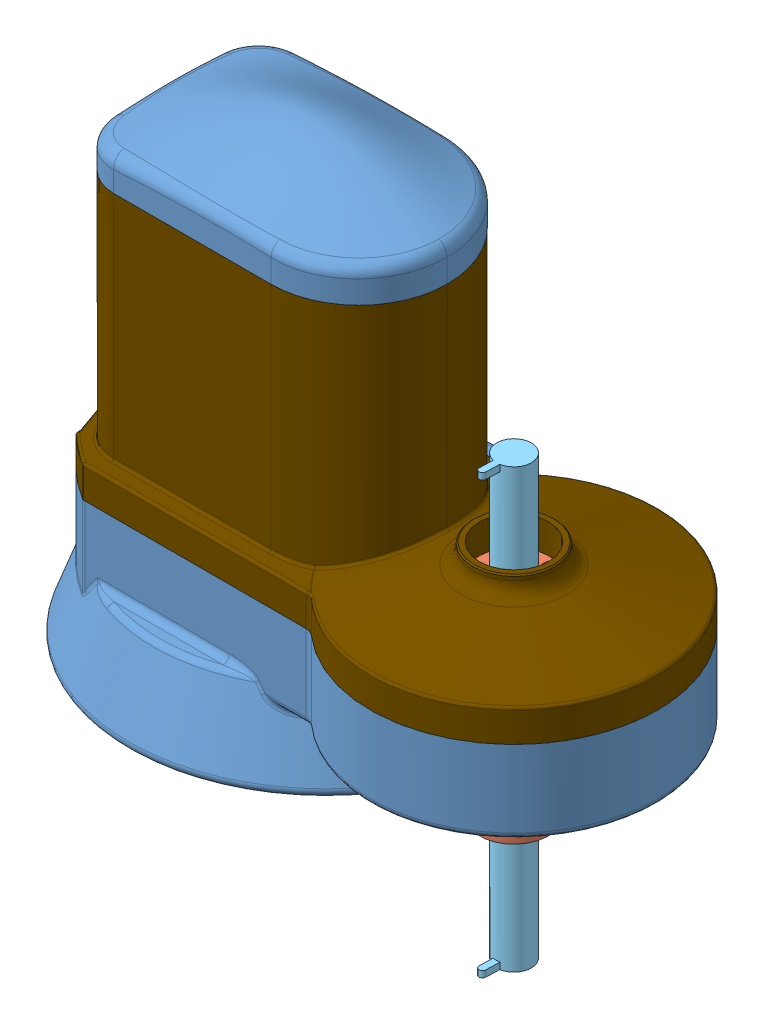
SolidWorks assembly 3rdgear-drive, configuration Default. Lengths in mm.
Overall size (465.65 484.88 318.82).
28 component instances, 23 part files, 43 mates.
Components (placement in the parent):
- block-1: block [Default] at (113.1408 70.2155 28.8884) size (448.1 118.47 307.8)
- lock3-1: lock3 [Default] at (1.0097 141.2577 38.6575) x (-0.07621 0 0.997092) z (0 -1 0) size (153.17 153.13 253.48) (flexible)
  - Part1 - Copy-1: Part1 - Copy [Default] at (-9.0719 9.4939 -127.4378) size (88.21 88.13 251.48)
  - 3rd Gear-1: 3rd Gear [Default] at (-9.0719 9.4939 -34.8178) x (0.981754 -0.190153 0) z (0.190153 0.981754 0) size (89.95 22.5 89.85)
  - 4th-1: 4th [Default] at (-9.0719 9.4939 -94.2778) x (0.930629 -0.365964 0) z (0.365964 0.930629 0) size (89.95 21.35 89.85)
  - 4th Mesh - Copy-1: 4th Mesh - Copy [Default] at (-9.0719 9.4939 -71.9278) x (0.992326 0.123646 0) z (-0.123646 0.992326 0) size (86.29 9.5 85.96)
  - gear3 mesh-1: gear3 mesh [Default] at (-9.0719 9.4939 -45.7778) x (0.370817 0.928706 0) z (-0.928706 0.370817 0) size (86.48 9.6 86.41)
  - Part3-1: Part3 [Default] at (-9.0719 9.4939 -49.6467) x (0.888761 -0.458371 0) z (-0.458371 -0.888761 0) size (106.2 22 106.2)
  - reverse-1: reverse [Default] at (-9.0719 9.4939 19.6169) x (0.555504 -0.831514 0) z (0.831514 0.555504 0) size (107.95 22 107.84)
  - 2nd gear-1: 2nd gear [Default] at (-9.0719 9.4939 -1.7178) x (0.052404 0.998626 0) z (-0.998626 0.052404 0) size (102.15 21.6 102.2)
  - reverse mesh-1: reverse mesh [Default] at (-9.0719 9.4939 4.6222) x (0.455242 -0.890368 0) z (0.890368 0.455242 0) size (80 8.5 80)
  - reverse mesh-2: reverse mesh [Default] at (-9.0719 9.4939 32.2222) x (-0.823291 -0.56762 0) z (-0.56762 0.823291 0) size (80 8.5 80)
  - 1st gear-1: 1st gear [Default] at (-9.0719 9.4939 41.2222) x (0.904554 0.426359 0) z (0.426359 -0.904554 0) size (115.11 23.6 115.04)
  - base-1: base [Default] at (-9.0719 9.4939 61.5422) x (-0.997092 0.07621 0) z (0.07621 0.997092 0) size (110 64.6 106)
- 1stshaft-1: 1stshaft [Default] at (-69.065 -17.9645 -6.5031) x (0.285789 0 -0.958293) z (0 1 0) size (77.36 77.56 310)
- bearing1-1: bearing1 [Default] at (-69.065 62.5355 -6.5031) x (0.746597 0 -0.665277) z (-0.665277 0 -0.746597) size (44.38 14.99 44.48)
- bearing2-1: bearing2 [Default] at (-69.065 250.9655 -6.5031) x (0.941122 0 -0.338068) z (0.338068 0 0.941122) size (59.38 14.43 59.22)
- rev-1: rev [Default] at (-83.7633 57.8155 52.0494) x (1 0 0) z (0 0 1) size (29.99 110 29.95)
- rev2-1: rev2 [Default] at (-83.7633 102.8155 52.0494) x (-0.962662 0 -0.270707) z (0.270707 0 -0.962662) size (59.97 20 59.87)
- blockup-1: blockup [Default] at (113.1408 95.0155 28.8884) size (399.91 205.51 224)
- blockup - Copy-1: blockup - Copy [Default] at (113.1408 95.0155 28.8884) size (222.45 55.95 144.6)
- diff-1: diff [Default] at (113.1408 30.6155 28.8884) x (-0.420076 0 -0.907489) z (0.907489 0 -0.420076) size (195.12 146.24 195.18)
- diffgearsmall-1: diffgearsmall [Default] at (115.5517 17.1155 34.0965) x (-0.420076 0 -0.907489) z (-0.528841 0.81265 0.2448) size (22.67 53.82 54.31)
- diffgearsmall-2: diffgearsmall [Default] at (110.73 17.1155 23.6804) x (0.420076 0 0.907489) z (0.876152 0.260519 -0.40557) size (22.67 53.82 54.31)
- diffgearbig-1: diffgearbig [Default] at (113.1408 17.0565 28.8884) x (0 1 0) z (-0.998475 0 -0.055198) size (22.67 61.01 61.56)
- diffgearbig-2: diffgearbig [Default] at (113.1408 17.7745 28.8884) x (0 -1 0) z (-0.870436 0 -0.492282) size (22.67 61.01 61.56)
- axle-1: axle [Default] at (113.1408 38.0355 28.8884) x (-0.999515 0 -0.031126) z (0 1 0) size (27 40.03 150)
- axle-2: axle [Default] at (113.1408 -3.2045 28.8884) x (0.999506 0 0.031435) z (0 -1 0) size (27 40.03 150)
Mates (geometry in assembly coordinates):
- Concentric1: concentric anti-aligned: cylinder of block-1 through (-7.7652 184.5592 28.8884) axis (0 -1 0) radius 32.5; cylinder of lock3-1/Part1 - Copy-1 through (-7.7652 17.2155 28.8884) axis (0 1 0) radius 17.5
- Concentric2: concentric aligned: cylinder of block-1 through (9.7348 15.2155 -16.1116) axis (0 1 0) radius 4; cylinder of lock3-1/base-1 through (9.7348 55.2155 -16.1116) axis (0 1 0) radius 4
- Coincident2: coincident anti-aligned: plane of block-1 through (-170.2735 70.2155 89.7919) normal (0 1 0); plane of lock3-1/base-1 through (17.939 70.2155 -28.6691) normal (0 -1 0)
- Concentric3: concentric anti-aligned: circle of block-1; cylinder of 1stshaft-1 through (-69.065 277.5355 -6.5031) axis (0 -1 0) radius 17.5
- Coincident3: coincident aligned: plane of lock3-1/4th-1 through (-7.7652 235.5355 28.8884) normal (0 1 0); plane of 1stshaft-1 through (-69.065 235.5355 -6.5031) normal (0 1 0)
- Concentric4: concentric aligned: cylinder of 1stshaft-1 through (-69.065 214.5355 -6.5031) axis (0 -1 0) radius 16.75; cone of bearing1-1 through (-69.065 65.7601 -6.5031) axis (0 -1 0)
- Tangent1: tangent: plane of 1stshaft-1 through (-69.065 77.5355 -6.5031) normal (0 1 0); torus of bearing1-1
- Concentric5: concentric anti-aligned: cone of 1stshaft-1 through (-69.065 251.5355 -6.5031) axis (0 1 0); cylinder of bearing2-1 through (-69.065 233.5355 -6.5031) axis (0 -1 0) radius 22.5514
- Distance1: distance = 1 mm anti-aligned: plane of bearing2-1 through (-45.7332 236.5355 -14.8843) normal (0 -1 0); plane of 1stshaft-1 through (-69.065 235.5355 -6.5031) normal (0 1 0)
- Coincident5: coincident anti-aligned: plane of block-1 through (37.6425 57.8155 -51.1116) normal (0 1 0); plane of rev-1 through (-83.7633 57.8155 52.0494) normal (0 -1 0)
- Concentric6: concentric aligned: cylinder of block-1 through (-83.7633 112.6419 52.0494) axis (0 -1 0) radius 10; cylinder of rev-1 through (-83.7633 167.8155 52.0494) axis (0 -1 0) radius 10
- Concentric7: concentric aligned: cylinder of rev-1 through (-83.7633 167.8155 52.0494) axis (0 -1 0) radius 10; cylinder of rev2-1 through (-83.7633 112.8155 52.0494) axis (0 -1 0) radius 15
- LimitDistance1: limit distance = 40 mm aligned: plane of rev-1 through (-83.7633 152.8155 52.0494) normal (0 1 0); plane of rev2-1 through (-83.7633 112.8155 52.0494) normal (0 1 0)
- Concentric8: concentric aligned: cylinder of block-1 through (113.1408 45.4155 28.8884) axis (0 1 0) radius 100; cylinder of blockup-1 through (113.1408 57.0155 28.8884) axis (0 1 0) radius 27
- Coincident6: coincident anti-aligned: plane of block-1 through (-170.2735 70.2155 89.7919) normal (0 1 0); plane of blockup-1 through (-170.2735 70.2155 89.7919) normal (0 -1 0)
- Concentric9: concentric anti-aligned: cylinder of 1stshaft-1 through (-69.065 277.5355 -6.5031) axis (0 -1 0) radius 17.5; cylinder of blockup-1 through (-69.065 176.23 -6.5031) axis (0 1 0) radius 17.5
- Coincident7: coincident anti-aligned: plane of blockup-1 through (-15.1026 275.7275 28.8884) normal (0 1 0); plane of blockup - Copy-1 through (-628.4678 275.7275 28.8884) normal (0 -1 0)
- Coincident8: coincident aligned: circle of blockup-1; circle of blockup - Copy-1
- Coincident9: coincident aligned: circle of blockup-1; circle of blockup - Copy-1
- Concentric10: concentric aligned: cylinder of block-1 through (113.1408 45.4155 28.8884) axis (0 1 0) radius 100; cylinder of diff-1 through (113.1408 30.5155 28.8884) axis (0 1 0) radius 16.5
- Concentric11: concentric anti-aligned: cylinder of diff-1 through (72.1574 17.1155 -59.6479) axis (0.420076 0 0.907489) radius 13.5; cylinder of diffgearsmall-1 through (140.3362 17.1155 87.6384) axis (-0.420076 0 -0.907489) radius 13.5
- Coincident10: coincident anti-aligned: plane of diff-1 through (121.9624 17.1155 47.9457) normal (0.420076 0 0.907489); plane of diffgearsmall-1 through (110.0932 27.3897 53.44) normal (-0.420076 0 -0.907489)
- Concentric12: concentric aligned: cylinder of diff-1 through (72.1574 17.1155 -59.6479) axis (0.420076 0 0.907489) radius 13.5; cylinder of diffgearsmall-2 through (85.9455 17.1155 -29.8615) axis (0.420076 0 0.907489) radius 13.5
- Coincident11: coincident anti-aligned: plane of diff-1 through (104.3192 17.1155 9.8312) normal (-0.420076 0 -0.907489); plane of diffgearsmall-2 through (101.8839 0.7014 10.9585) normal (0.420076 0 0.907489)
- Distance2: distance = 1 mm aligned: plane of diff-1 through (113.1408 58.8155 28.8884) normal (0 1 0); plane of block-1 through (37.6425 57.8155 -51.1116) normal (0 1 0)
- Concentric13: concentric anti-aligned: cylinder of diff-1 through (113.1408 30.5155 28.8884) axis (0 1 0) radius 16.5; cylinder of diffgearbig-2 through (113.1408 76.7745 28.8884) axis (0 -1 0) radius 13.5
- Distance3: distance = 56 mm anti-aligned: plane of diffgearbig-2 through (101.5901 33.0355 16.9216) normal (0 -1 0); plane of diff-1 through (113.1408 89.0355 28.8884) normal (0 1 0)
- Concentric14: concentric anti-aligned: cylinder of diff-1 through (113.1408 2.2455 28.8884) axis (0 -1 0) radius 14.2; cylinder of diffgearbig-1 through (113.1408 -41.9435 28.8884) axis (0 1 0) radius 13.5
- Distance5: distance = 59 mm anti-aligned: plane of diffgearbig-1 through (109.9141 1.7955 45.2045) normal (0 1 0); plane of diff-1 through (113.1408 -57.2045 28.8884) normal (0 -1 0)
- GearMate10: gear = 63.1 : 65 mm: circle of 1stshaft-1; circle of lock3-1/4th-1
- GearMate11: gear = 73.33 : 53 mm: circle of 1stshaft-1; circle of lock3-1/3rd Gear-1
- GearMate12: gear = 88 : 39 mm: circle of 1stshaft-1; circle of lock3-1/2nd gear-1
- GearMate13: gear = 103 : 26 mm: circle of 1stshaft-1; circle of lock3-1/1st gear-1
- GearMate15: gear = 39.4 : 39.4 mm: circle of diffgearsmall-1; circle of diffgearbig-2
- GearMate16: gear = 39.4 : 39.4 mm: circle of diffgearsmall-2; circle of diffgearbig-1
- GearMate17: gear = 39.4 : 39.4 mm: circle of diffgearsmall-1; circle of diffgearbig-1
- Concentric15: concentric anti-aligned: cylinder of diff-1 through (113.1408 30.5155 28.8884) axis (0 1 0) radius 16.5; cylinder of axle-1 through (113.1408 188.0355 28.8884) axis (0 -1 0) radius 13.5
- Distance6: distance = 5 mm aligned: plane of axle-1 through (113.1408 38.0355 28.8884) normal (0 -1 0); plane of diffgearbig-2 through (119.2279 33.0355 13.4103) normal (0 -1 0)
- Concentric16: concentric anti-aligned: cylinder of diff-1 through (113.1408 2.2455 28.8884) axis (0 -1 0) radius 14.2; cylinder of axle-2 through (113.1408 -153.2045 28.8884) axis (0 1 0) radius 13.5
- Distance7: distance = 5 mm aligned: plane of axle-2 through (113.1408 -3.2045 28.8884) normal (0 1 0); plane of diffgearbig-1 through (126.642 1.7955 38.6015) normal (0 1 0)
- GearMate18: gear = 27 : 39.4 mm: circle of diffgearbig-2; circle of axle-1
- GearMate19: gear = 27 : 27 mm: circle of axle-2; circle of axle-1
- GearMate20: gear = 183.6 : 45 mm: circle of lock3-1/Part1 - Copy-1; circle of diff-1
